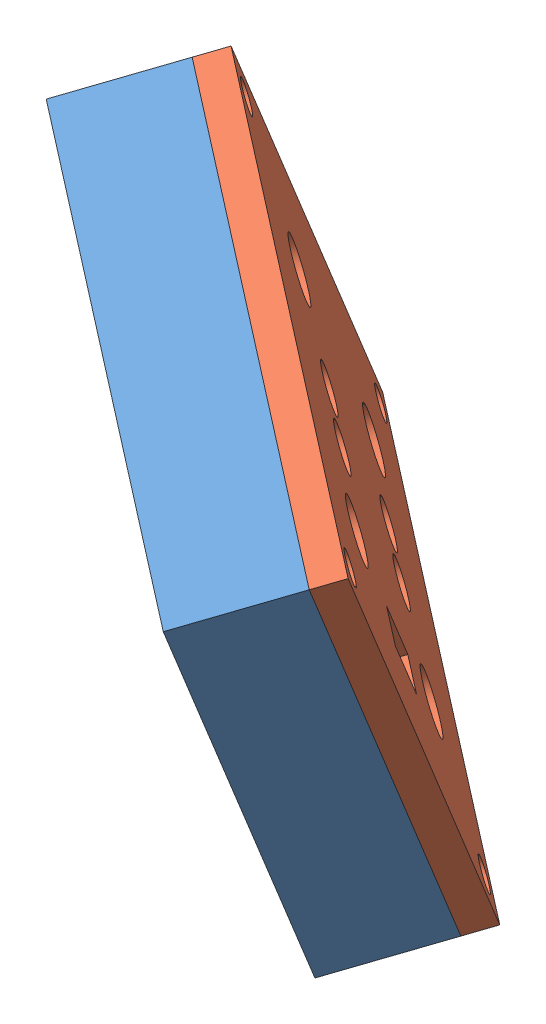
SolidWorks assembly Box_assembly, configuration Default. Lengths in mm.
Overall size (68.78 85.46 75.84).
2 component instances, 2 part files, 4 mates.
Components (placement in the parent):
- box_under2-1: box_under2 [Default] at (-93.5411 -28.0856 79.9814) x (0.780367 -0.332143 0.52982) z (0.097264 0.901434 0.421848) size (65 15 65)
- lid_final-1: lid_final [Default] at (-81.8046 -22.81 66.0021) x (0.780367 -0.332143 0.52982) z (-0.097264 -0.901434 -0.421848) size (65 4 65)
Mates (geometry in assembly coordinates):
- Coincident9: coincident: point of box_under2-1; point of lid_final-1
- Coincident10: coincident: point of box_under2-1; point of lid_final-1
- Coincident11: coincident: point of box_under2-1; point of lid_final-1
- Coincident12: coincident: point of box_under2-1; point of lid_final-1
